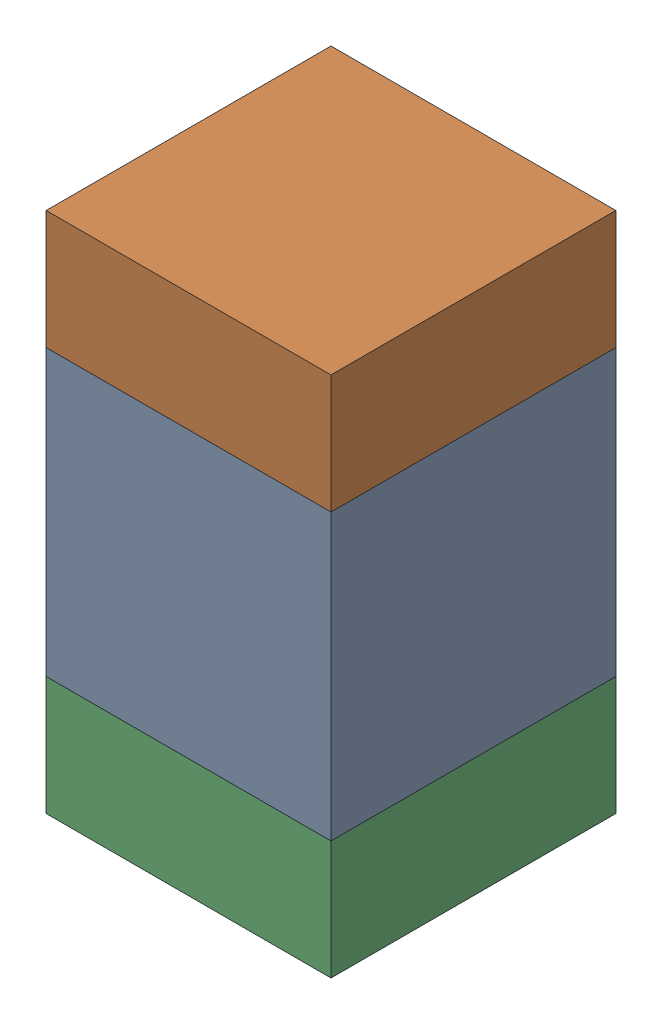
SolidWorks assembly C118_2PCB, configuration Default. Lengths in mm.
Overall size (0.6 1.1 0.6).
6 component instances, 2 part files, 0 mates.
Components (placement in the parent):
- 761606048-1: 761606048 [Default] at (114.8 93.8 0) size (0.6 0.6 0.6)
  - Extruded_9-1: Extruded_9 [Default] at origin size (0.6 0.6 0.6)
- 854785296-1: 854785296 [Default] at (114.8 94.225 0) size (0.6 0.25 0.6)
  - Extruded_10-1: Extruded_10 [Default] at origin size (0.6 0.25 0.6)
- 854785296-2: 854785296 [Default] at (114.8 93.375 0) size (0.6 0.25 0.6)
  - Extruded_10-1: Extruded_10 [Default] at origin size (0.6 0.25 0.6)
